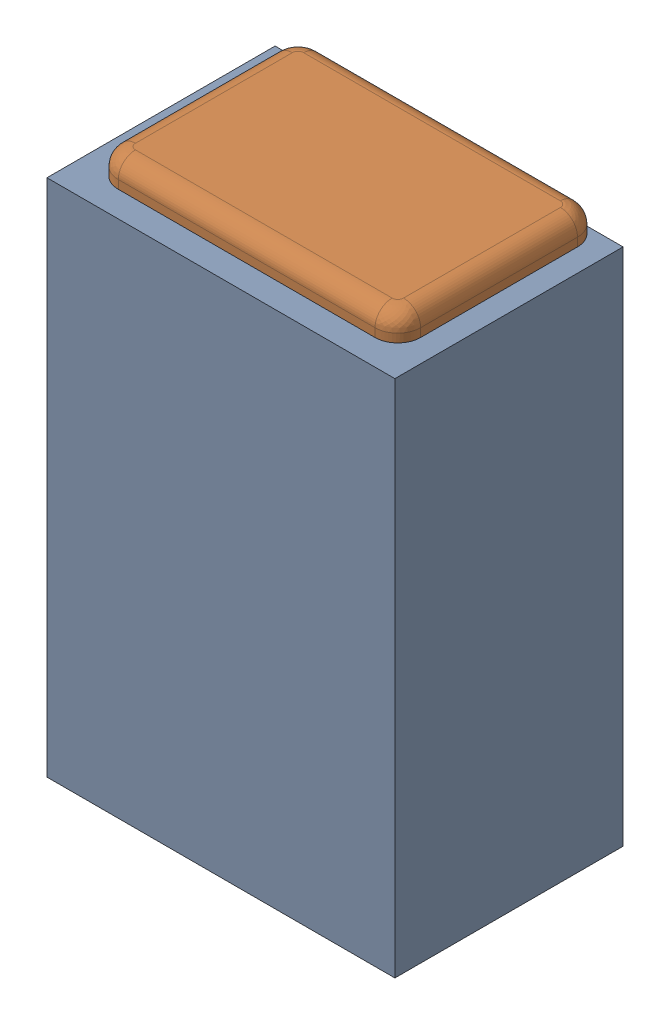
SolidWorks assembly C14, configuration Default. Lengths in mm.
Overall size (0.61 1 0.4).
3 component instances, 2 part files, 0 mates.
Components (placement in the parent):
- 1088881848-1: 1088881848 [Default] at (12.275 34.65 0) size (0.61 0.91 0.4)
  - Extruded-1-1: Extruded-1 [Default] at origin size (0.61 0.91 0.4)
- C0402-1: C0402 [Default] at (12.2751 34.6499 0) x (0 -1 0) z (-1 0 0) size (1 0.36 0.54)
